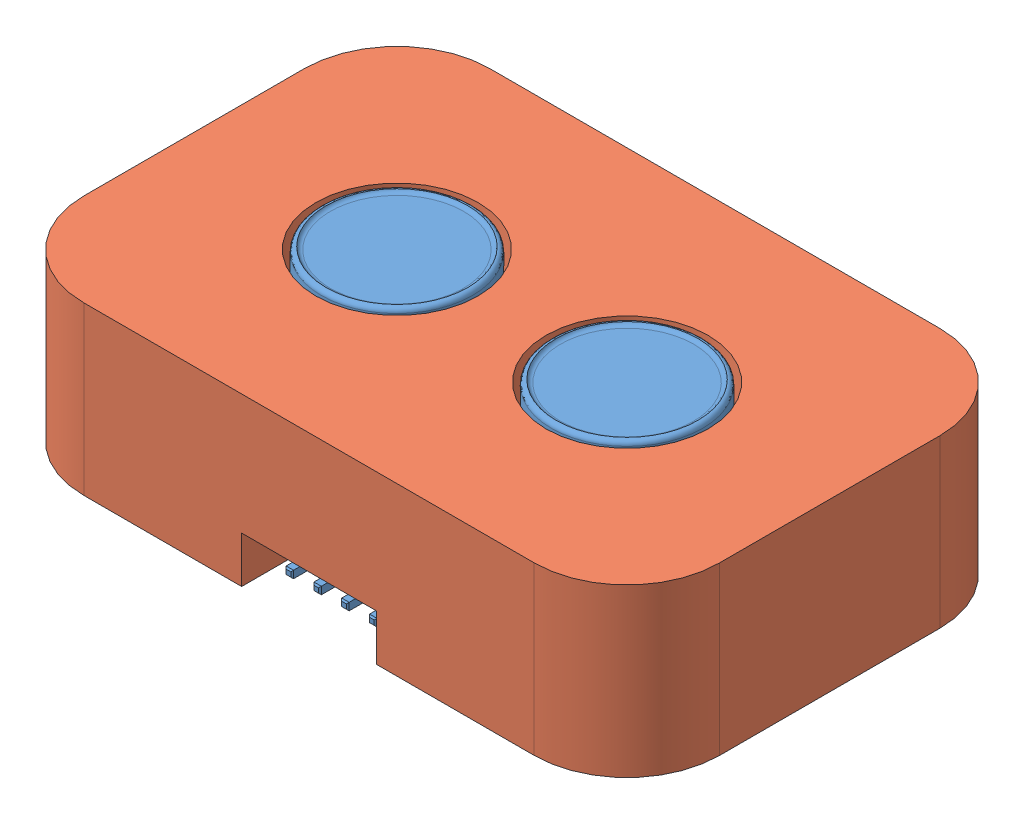
SolidWorks assembly Assem1, configuration Default. Lengths in mm.
Overall size (68.6 18.65 43.8).
2 component instances, 2 part files, 4 mates.
Components (placement in the parent):
- Ultrasonic-sensor-1: Ultrasonic-sensor [Default] at (9.8726 18.1883 35.6136) size (45.6 18.65 28.52)
- Part 2-1: Part 2 [Default] at (9.8726 19.8383 35.6136) x (1 0 0) z (0 1 0) size (68.6 43.8 18)
Mates (geometry in assembly coordinates):
- InPlace1: in place: plane of Ultrasonic-sensor-1 through (9.8726 19.8383 35.6136) normal (0 1 0); plane of ? through (0 19.8383 0) normal (0 1 0); moOrthogonalPlaneRef_w of Ultrasonic-sensor-1 through (9.8726 19.8383 35.6136) normal (0 1 0); plane of ? through (0 19.8383 0) normal (0 0 -1); plane of Ultrasonic-sensor-1 through (9.8726 19.8383 35.6136) normal (0 1 0); plane of ? through (0 19.8383 0) normal (1 0 0); plane of Ultrasonic-sensor-1 through (9.8726 19.8383 35.6136) normal (0 1 0); unknown of Part 2-1
- Coincident1: coincident aligned: plane of ?; plane of ?
- Coincident2: coincident aligned: moOrthogonalPlaneRef_w of Ultrasonic-sensor-1 through (9.8726 19.8383 35.6136) normal (0 0 -1); plane of Ultra sonic cover^Assem1-1 through (9.8726 19.8383 35.6136) normal (0 0 -1)
- Coincident3: coincident anti-aligned: moOrthogonalPlaneRef_w of Ultrasonic-sensor-1 through (9.8726 19.8383 35.6136) normal (-1 0 0); plane of Ultra sonic cover^Assem1-1 through (9.8726 19.8383 35.6136) normal (1 0 0)
